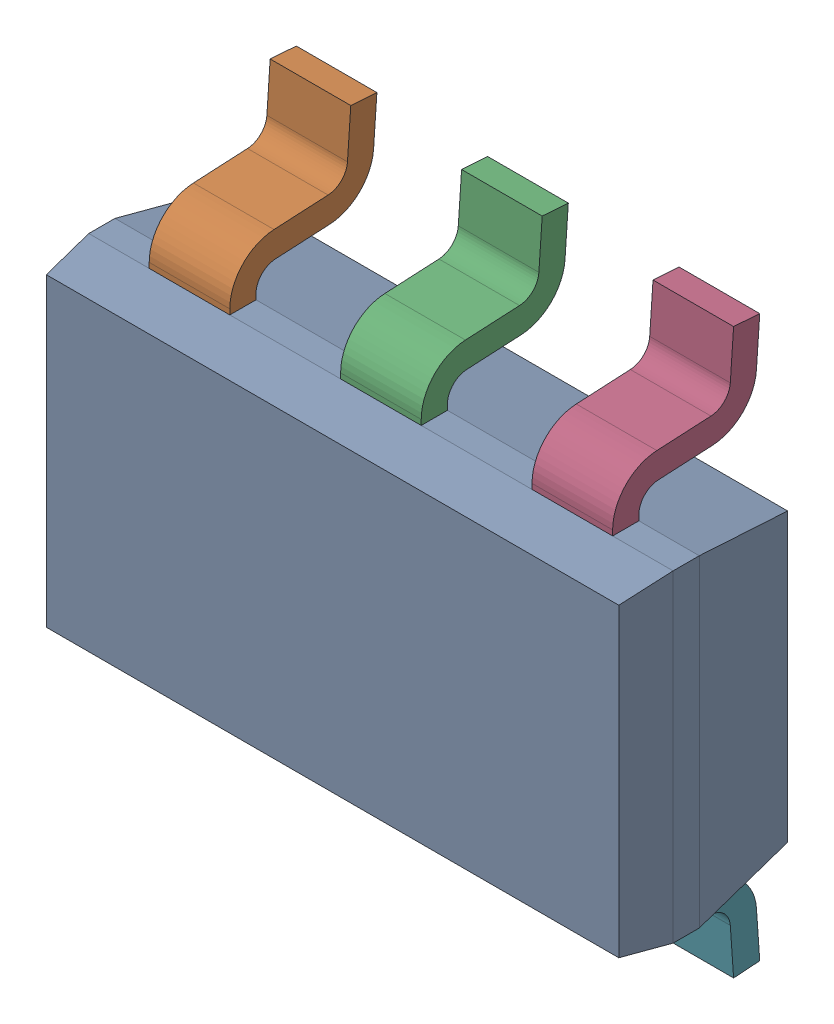
SolidWorks assembly U6, configuration ﾃﾞﾌｫﾙﾄ. Lengths in mm.
Overall size (2.9 2.8 0.97).
8 component instances, 2 part files, 0 mates.
Components (placement in the parent):
- DDC0006A-1: DDC0006A [ﾃﾞﾌｫﾙﾄ] at (39.37 15.875 0) x (0 1 0) z (0 0 1) size (2.8 2.9 0.97)
  - BODY-SOT-1: BODY-SOT [ﾃﾞﾌｫﾙﾄ] at (0 0 0.73) x (0 1 0) z (1 0 0) size (2.9 0.87 1.6)
  - LEAD-SOT-1: LEAD-SOT [ﾃﾞﾌｫﾙﾄ] at (0.9409 0.95 0.25) x (0 1 0) z (1 0 0) size (0.4 0.73 0.6)
  - LEAD-SOT-2: LEAD-SOT [ﾃﾞﾌｫﾙﾄ] at (0.9409 0 0.25) x (0 1 0) z (1 0 0) size (0.4 0.73 0.6)
  - LEAD-SOT-3: LEAD-SOT [ﾃﾞﾌｫﾙﾄ] at (0.9409 -0.95 0.25) x (0 1 0) z (1 0 0) size (0.4 0.73 0.6)
  - LEAD-SOT-4: LEAD-SOT [ﾃﾞﾌｫﾙﾄ] at (-0.9409 0.95 0.25) x (0 -1 0) z (-1 0 0) size (0.4 0.73 0.6)
  - LEAD-SOT-5: LEAD-SOT [ﾃﾞﾌｫﾙﾄ] at (-0.9409 0 0.25) x (0 -1 0) z (-1 0 0) size (0.4 0.73 0.6)
  - LEAD-SOT-6: LEAD-SOT [ﾃﾞﾌｫﾙﾄ] at (-0.9409 -0.95 0.25) x (0 -1 0) z (-1 0 0) size (0.4 0.73 0.6)
